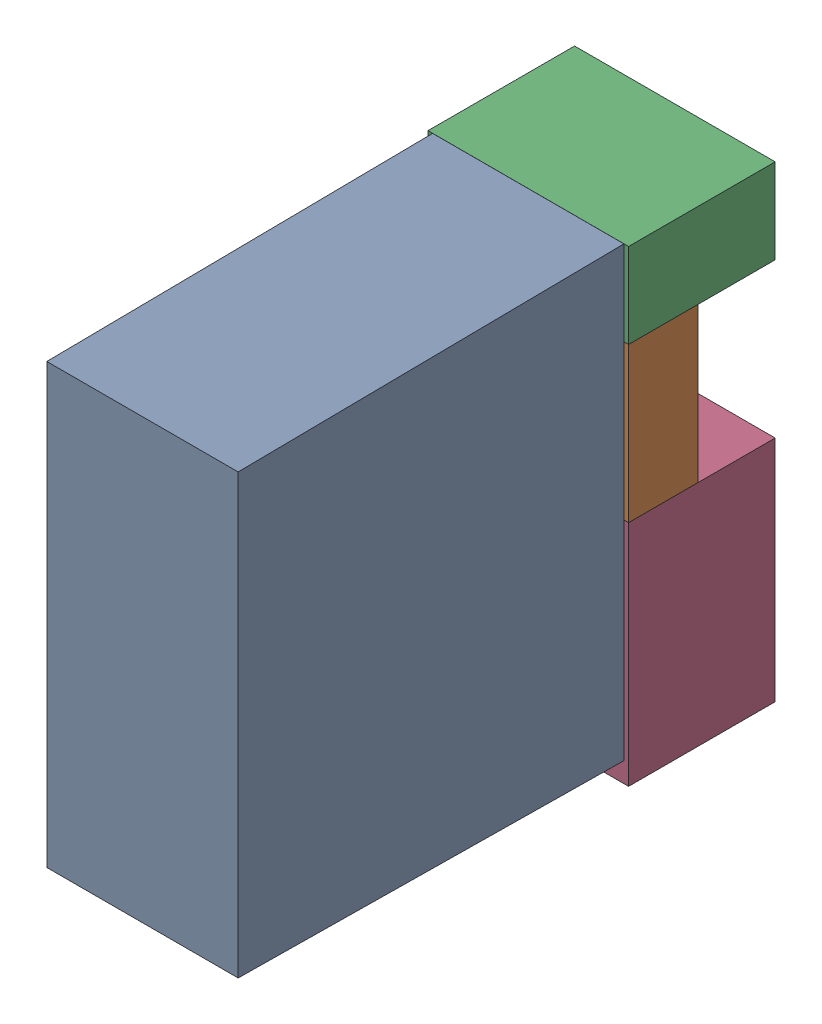
SolidWorks assembly K13, configuration Default. Lengths in mm.
Overall size (13 30.3 34.5).
7 component instances, 4 part files, 0 mates.
Components (placement in the parent):
- relais_40_61_8_006_0000-1: relais_40_61_8_006_0000 [Default] at (194.945 15.7216 9.5) x (0 1 0) z (1 0 0) size (29 30 12.4)
- 1151725064-1: 1151725064 [Default] at (194.945 34.225 5) size (13 10 4.5)
  - Extruded_3-1: Extruded_3 [Default] at origin size (13 10 4.5)
- 1151724928-1: 1151724928 [Default] at (194.945 41.975 0) size (13 5.5 9.5)
  - Extruded_2-1: Extruded_2 [Default] at origin size (13 5.5 9.5)
- 1151724792-1: 1151724792 [Default] at (194.945 21.825 0) size (13 14.8 9.5)
  - Extruded_4-1: Extruded_4 [Default] at origin size (13 14.8 9.5)
